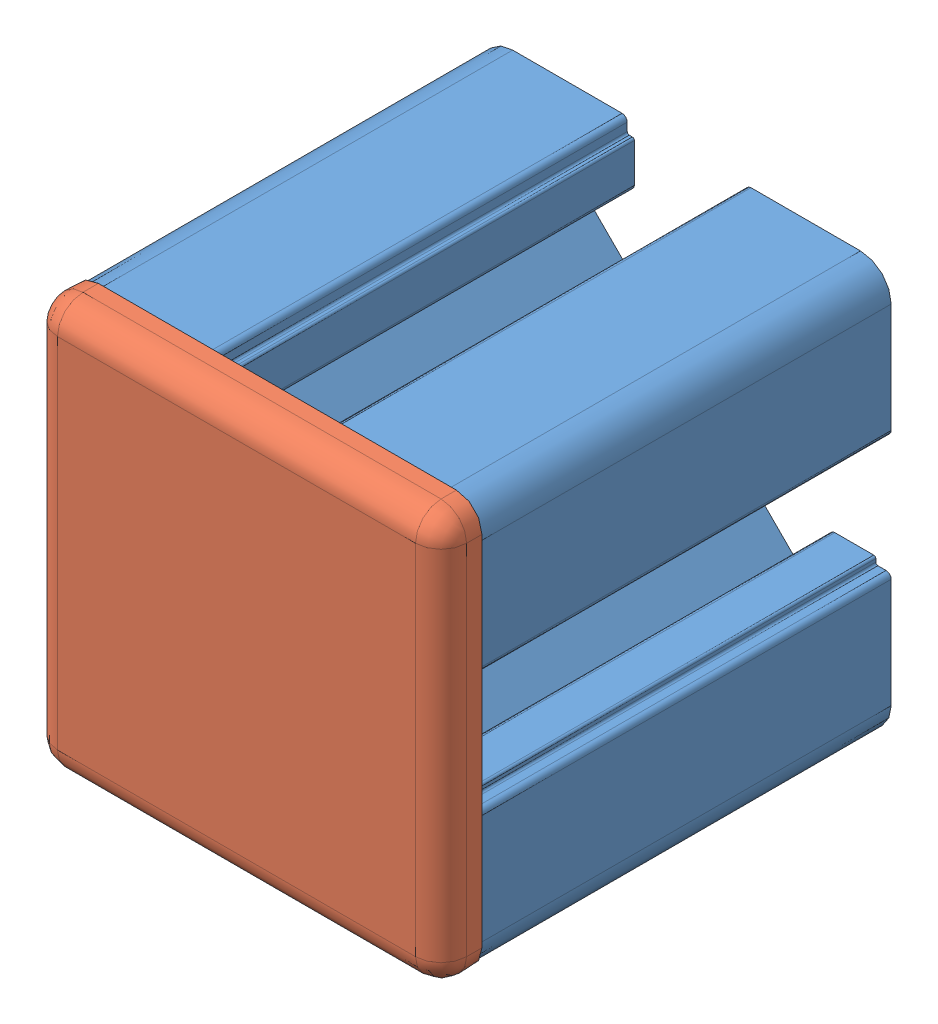
SolidWorks assembly Заглушка40х40СБ, configuration По умолчанию. Lengths in mm.
Overall size (40 40 44).
2 component instances, 2 part files, 6 mates.
Components (placement in the parent):
- 40х40 заглушка-1: 40х40 заглушка [По умолчанию] at origin size (40 40 40)
- Заглушка торцевая 40х40-1: Заглушка торцевая 40х40 [По умолчанию] at (0 0 42) x (0 0 -1) z (1 0 0) size (12.18 40 40)
Mates (geometry in assembly coordinates):
- Совпадение2: coincident: point of 40х40 заглушка-1
- Параллельность1: parallel anti-aligned: plane of 40х40 заглушка-1 through (0 -20 40) normal (0 -1 0)
- Совпадение4: coincident anti-aligned: plane of 40х40 заглушка-1 through (0 0 0) normal (0 0 -1)
- Совпадение5: coincident anti-aligned: plane of 40х40 заглушка-1 through (0 0 40) normal (0 0 1); plane of Заглушка торцевая 40х40-1 through (-20 -20 40) normal (0 0 -1)
- Совпадение6: coincident aligned: plane of 40х40 заглушка-1 through (0 20 40) normal (0 1 0); plane of Заглушка торцевая 40х40-1 through (-20 20 41.5) normal (0 1 0)
- Совпадение7: coincident aligned: plane of 40х40 заглушка-1 through (20 0 40) normal (1 0 0); plane of Заглушка торцевая 40х40-1 through (20 17.5 41.5) normal (1 0 0)
